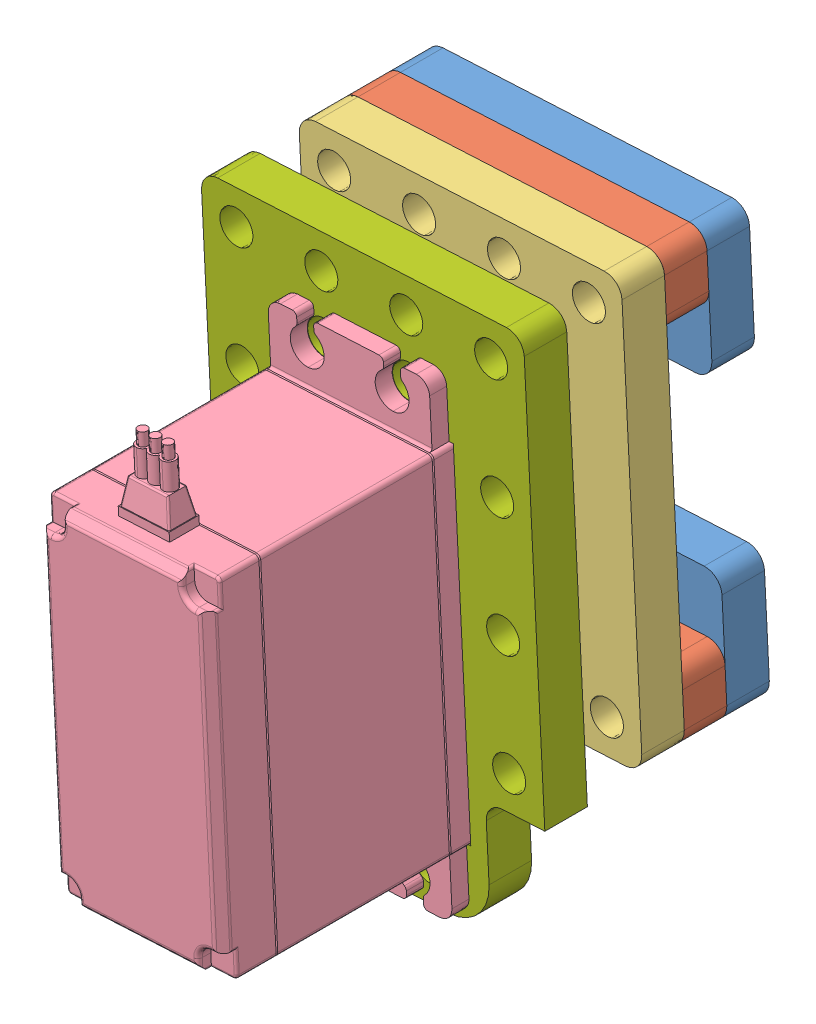
SolidWorks assembly ASM ELEVATOR, configuration Default. Lengths in mm.
Overall size (41.16 64.48 55.5).
9 component instances, 7 part files, 23 mates.
Components (placement in the parent):
- X2 3mm ELEV SUP1-1: X2 3mm ELEV SUP1 [Default] at (51.4546 16.8456 114.9428) x (-0.998683 -0.051314 0) z (0.051314 -0.998683 0) size (38 5 15)
- ELEV SUP2-1: ELEV SUP2 [Default] at (89.4045 18.7955 119.9428) x (-0.998683 -0.051314 0) z (0.051314 -0.998683 0) size (38 5 8)
- ELEV SUP3-1: ELEV SUP3 [Default] at (91.9302 -30.3596 124.9428) x (0.998683 0.051314 0) z (-0.051314 0.998683 0) size (38 5 49.22)
- MG995.step-1: MG995.step [Default] at (72.2055 -16.7438 165.4428) x (-0.051314 0.998683 0) z (0 0 -1) size (55.5 20 44.5)
- X2 3mm ELEV SUP1-2: X2 3mm ELEV SUP1 [Default] at (53.9803 -32.3096 109.9428) x (-0.998683 -0.051314 0) z (-0.051314 0.998683 0) size (38 5 15)
- ELEV ATTACH1-1: ELEV ATTACH1 [Default] at (71.6924 -6.757 119.9428) x (0.551223 0.834358 0) z (0 0 1) size (21 21 5.5)
- attach 2-1: attach 2 [Default] at (71.6924 -6.757 114.9428) x (0.834358 -0.551223 0) z (0 0 1) size (25 24.95 5)
- ELEV SUP2-3: ELEV SUP2 [Default] at (53.9803 -32.3096 119.9428) x (0.998683 0.051314 0) z (-0.051314 0.998683 0) size (38 5 8)
- new supportv3 servo 6-1: new supportv3 servo 6 [Default] at (51.4546 16.8456 131.4428) x (-0.051314 0.998683 0) z (0 0 1) size (62.61 38 5)
Mates (geometry in assembly coordinates):
- Concentric12: concentric aligned: cylinder of MG995.step-1 through (71.6924 -6.757 125.9428) axis (0 0 1) radius 2; cylinder of ELEV ATTACH1-1 through (71.6924 -6.757 120.9428) axis (0 0 1) radius 2.75
- Coincident30: coincident anti-aligned: plane of MG995.step-1 through (71.6924 -6.757 120.9428) normal (0 0 -1); plane of ELEV ATTACH1-1 through (71.6924 -6.757 120.9428) normal (0 0 1)
- Concentric13: concentric aligned: cylinder of ELEV ATTACH1-1 through (71.6924 -6.757 123.4428) axis (0 0 -1) radius 1.6; cylinder of attach 2-1 through (71.6924 -6.757 119.9428) axis (0 0 -1) radius 1.6
- Concentric15: concentric anti-aligned: cylinder of ELEV ATTACH1-1 through (73.6856 0.7953 118.4428) axis (0 0 1) radius 1; cylinder of attach 2-1 through (73.6856 0.7953 119.9428) axis (0 0 -1) radius 1
- Coincident48: coincident anti-aligned: plane of ELEV SUP2-1 through (53.7598 10.9561 119.9428) normal (0 0 1); plane of ELEV SUP3-1 through (87.5098 16.6955 119.9428) normal (0 0 -1)
- Coincident51: coincident anti-aligned: plane of X2 3mm ELEV SUP1-1 through (54.119 3.9653 114.9428) normal (0 0 1); plane of ELEV SUP2-1 through (53.7598 10.9561 114.9428) normal (0 0 -1)
- Coincident52: coincident aligned: plane of X2 3mm ELEV SUP1-1 through (87.4072 18.6929 109.9428) normal (-0.051314 0.998683 0); plane of ELEV SUP2-1 through (87.4072 18.6929 114.9428) normal (-0.051314 0.998683 0)
- Coincident54: coincident anti-aligned: plane of X2 3mm ELEV SUP1-2 through (55.3106 -19.2241 114.9428) normal (0 0 1); plane of ELEV SUP2-3 through (89.625 -24.4701 114.9428) normal (0 0 -1)
- Coincident57: coincident aligned: plane of attach 2-1 through (71.6924 -6.757 114.9428) normal (0 0 -1); plane of ELEV SUP2-3 through (89.625 -24.4701 114.9428) normal (0 0 -1)
- Coincident58: coincident anti-aligned: plane of ELEV SUP3-1 through (87.5098 16.6955 119.9428) normal (0 0 -1); plane of ELEV SUP2-3 through (89.625 -24.4701 119.9428) normal (0 0 1)
- Coincident67: coincident aligned: plane of ELEV SUP2-1 through (51.5572 14.8482 114.9428) normal (-0.998683 -0.051314 0); plane of ELEV SUP2-3 through (53.8776 -30.3122 114.9428) normal (-0.998683 -0.051314 0)
- Coincident72: coincident aligned: plane of ELEV SUP3-1 through (91.8276 -28.3623 119.9428) normal (0.998683 0.051314 0); plane of ELEV SUP2-3 through (91.8276 -28.3623 114.9428) normal (0.998683 0.051314 0)
- Coincident73: coincident aligned: plane of ELEV SUP3-1 through (55.9776 -32.2069 119.9428) normal (0.051314 -0.998683 0); plane of ELEV SUP2-3 through (55.9776 -32.2069 114.9428) normal (0.051314 -0.998683 0)
- Coincident74: coincident aligned: plane of ELEV SUP2-1 through (87.4072 18.6929 114.9428) normal (-0.051314 0.998683 0); plane of ELEV SUP3-1 through (53.4519 16.9482 119.9428) normal (-0.051314 0.998683 0)
- Coincident76: coincident anti-aligned: plane of MG995.step-1 through (83.2187 -36.2043 129.4428) normal (0.051314 -0.998683 0); plane of new supportv3 servo 6-1 through (63.245 -37.2306 136.4428) normal (-0.051314 0.998683 0)
- Coincident77: coincident anti-aligned: plane of MG995.step-1 through (83.2187 -36.2043 129.4428) normal (0.998683 0.051314 0); plane of new supportv3 servo 6-1 through (83.2187 -36.2043 136.4428) normal (-0.998683 -0.051314 0)
- Coincident78: coincident anti-aligned: plane of MG995.step-1 through (72.2055 -16.7438 136.4428) normal (0 0 -1); plane of new supportv3 servo 6-1 through (87.5098 16.6955 136.4428) normal (0 0 1)
- Coincident80: coincident aligned: plane of X2 3mm ELEV SUP1-2 through (89.9328 -30.4622 114.9428) normal (0.051314 -0.998683 0); plane of ELEV SUP2-3 through (55.9776 -32.2069 114.9428) normal (0.051314 -0.998683 0)
- Coincident81: coincident aligned: plane of X2 3mm ELEV SUP1-2 through (91.8276 -28.3623 114.9428) normal (0.998683 0.051314 0); plane of ELEV SUP2-3 through (91.8276 -28.3623 114.9428) normal (0.998683 0.051314 0)
- Coincident82: coincident aligned: plane of ELEV SUP3-1 through (91.8276 -28.3623 119.9428) normal (0.998683 0.051314 0); plane of new supportv3 servo 6-1 through (89.5071 16.7982 136.4428) normal (0.998683 0.051314 0)
- Coincident85: coincident aligned: plane of X2 3mm ELEV SUP1-1 through (89.5071 16.7982 109.9428) normal (0.998683 0.051314 0); plane of ELEV SUP3-1 through (91.8276 -28.3623 119.9428) normal (0.998683 0.051314 0)
- Concentric16: concentric aligned: cylinder of ELEV SUP3-1 through (85.615 14.5956 124.9428) axis (0 0 -1) radius 1.95; cylinder of new supportv3 servo 6-1 through (85.615 14.5956 136.4428) axis (0 0 -1) radius 1.95
- Coincident86: coincident anti-aligned: plane of ELEV ATTACH1-1 through (71.6924 -6.757 119.9428) normal (0 0 -1); plane of attach 2-1 through (71.6924 -6.757 119.9428) normal (0 0 1)
